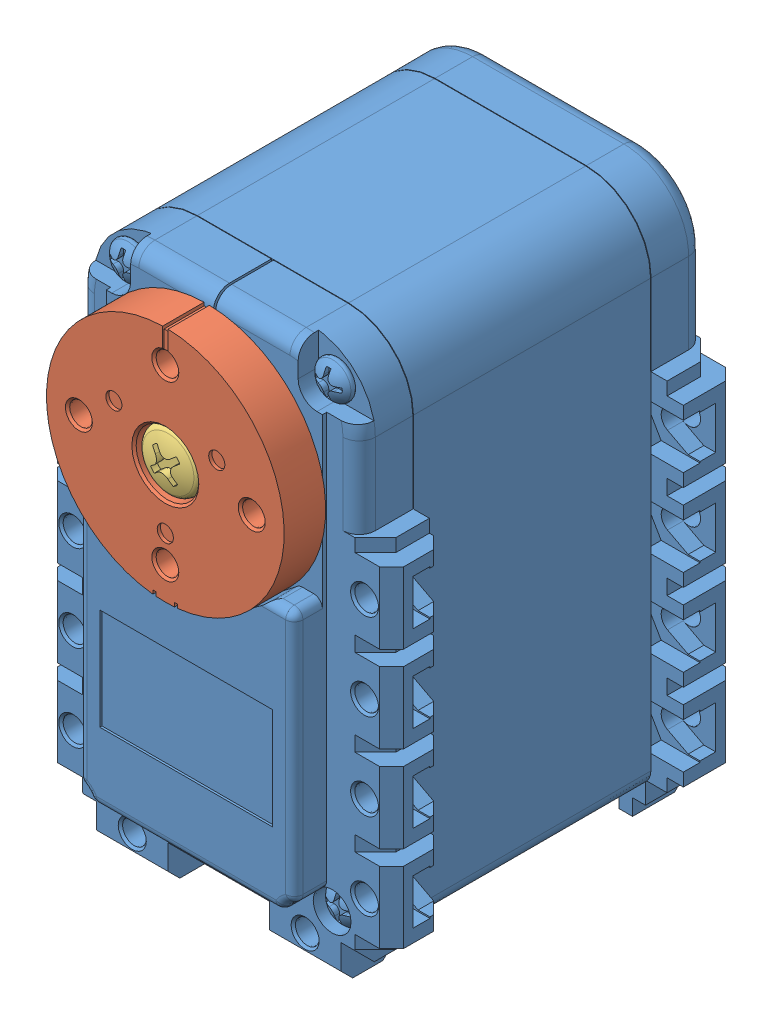
SolidWorks assembly AX-12_18A, configuration Défaut. Lengths in mm.
Overall size (32 50.04 40.32).
3 component instances, 3 part files, 8 mates.
Components (placement in the parent):
- dynamixel_AXseries-1: dynamixel_AXseries [Défaut] at origin size (32 50.04 38.37)
- AX12_horn-1: AX12_horn [Défaut] at (0 0 19.1) x (0 1 0) z (0 0 1) size (22 22 6.7)
- BHS_M2_6X8-1: BHS_M2_6X8 [Défaut] at (0 0 19.55) x (0.628847 -0.777529 0) z (-0.777529 -0.628847 0) size (5.5 9.6 5.5)
Mates (geometry in assembly coordinates):
- Concentric2: concentric aligned: cylinder of dynamixel_AXseries-1 through (0 0 17.9) axis (0 0 1) radius 2.9; cylinder of AX12_horn-1 through (0 0 21.8) axis (0 0 1) radius 2.9
- Angle1: planar angle = 0 rad anti-aligned: plane of AX12_horn-1 through (0.925 0.9134 22.556) normal (-1 0 0); plane of dynamixel_AXseries-1 through (0.45 1.3784 17.9) normal (1 0 0)
- Coincident3: coincident anti-aligned: plane of dynamixel_AXseries-1 through (0 0 17.9) normal (0 0 1); plane of AX12_horn-1 through (0 0 17.9) normal (0 0 -1)
- Concentric3: concentric anti-aligned: cylinder of dynamixel_AXseries-1 through (0 0 -2.325) axis (0 0 1) radius 1.15; cylinder of BHS_M2_6X8-1 through (0 0 21.63) axis (0 0 -1) radius 1.3
- Coincident4: coincident anti-aligned: plane of AX12_horn-1 through (0 0 19.55) normal (0 0 1); plane of BHS_M2_6X8-1 through (0 0 19.55) normal (0 0 -1)
- Coincident5: coincident aligned: plane of dynamixel_AXseries-1 through (0 0 0) normal (0 0 1); plane of assembly through (0 0 0) normal (0 0 1)
- Coincident6: coincident aligned: plane of dynamixel_AXseries-1 through (0 0 0) normal (0 1 0); plane of assembly through (0 0 0) normal (0 1 0)
- Coincident7: coincident aligned: plane of dynamixel_AXseries-1 through (0 0 0) normal (1 0 0); plane of assembly through (0 0 0) normal (1 0 0)
